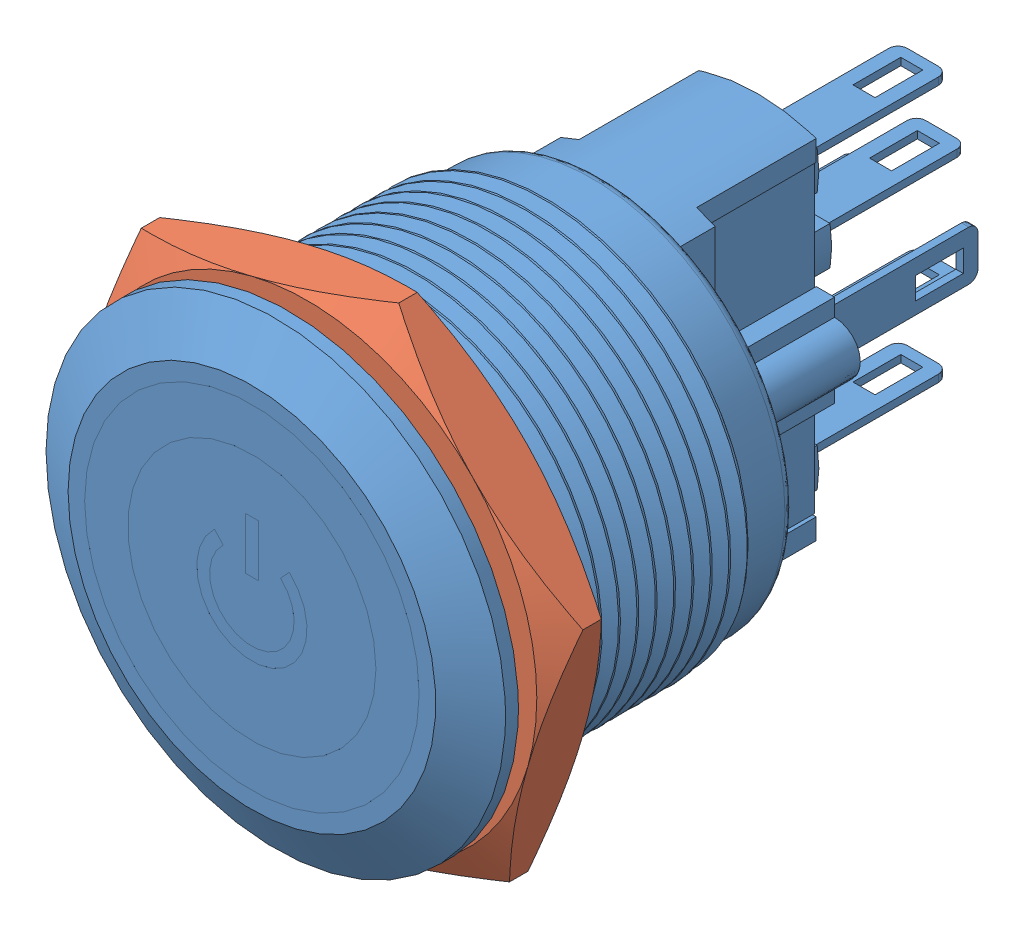
SolidWorks assembly 22mm不锈钢按钮, configuration 默认. Lengths in mm.
Overall size (32.01 34.65 37.5).
2 component instances, 2 part files, 2 mates.
Components (placement in the parent):
- 22mm按钮-1: 22mm按钮 [默认] at (2.967 1.591 54.25) size (25 25 37.5)
- 22mm金属按钮螺母-1: 22mm金属按钮螺母 [默认] at (2.967 1.591 53.25) x (-0.276521 -0.961008 0) z (0.961008 -0.276521 0) size (28.87 3.94 25)
Mates (geometry in assembly coordinates):
- 同心1: concentric anti-aligned: cylinder of 22mm按钮-1 through (2.967 1.591 40.25) axis (0 0 -1) radius 10.5; circle of 22mm金属按钮螺母-1
- 距离1: distance = 1 mm anti-aligned: plane of 22mm金属按钮螺母-1 through (2.967 1.591 53.25) normal (0 0 1); plane of 22mm按钮-1 through (2.967 1.591 54.25) normal (0 0 -1)
